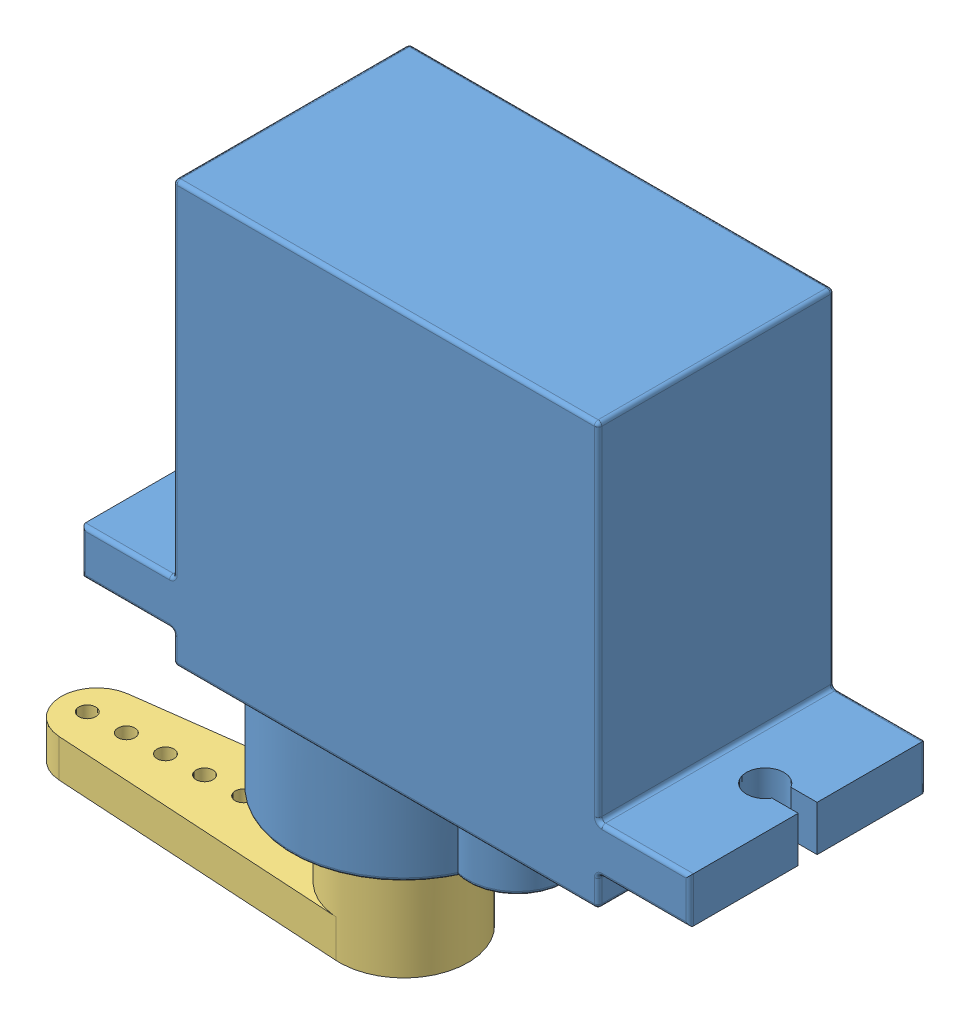
SolidWorks assembly MG90S 金属舵机装配体 2018, configuration 默认. Lengths in mm.
Overall size (39.1 34.99 12.5).
3 component instances, 3 part files, 7 mates.
Components (placement in the parent):
- MG90S 金属舵机渲染2018-1: MG90S 金属舵机渲染2018 [默认] x (-1 0 0) z (0 0 -1) size (32.2 32.2 12.5)
- cross recessed pan head screws gb(GB_CROSS_SCREWS_TYPE1 M2X4-4  H type-N)2018-1: cross recessed pan head screws gb(GB_CROSS_SCREWS_TYPE1 M2X4-4  H type-N)2018 [默认] at (-5.29 -23.85 0) x (0 1 0) z (-0.996226 0 -0.086793) size (5.59 4 4)
- MG90S 金属舵机单舵臂渲染2018-1: MG90S 金属舵机单舵臂渲染2018 [默认] at (-5.29 -23.25 0) x (0.999366 0 -0.035616) z (0 -1 0) size (21 6.8 4.7)
Mates (geometry in assembly coordinates):
- 重合1: coincident anti-aligned: plane of MG90S 金属舵机渲染2018-1 through (0 0 0) normal (0 0 -1)
- 重合2: coincident aligned: plane of MG90S 金属舵机渲染2018-1 through (0 0 0) normal (0 1 0)
- 重合3: coincident anti-aligned: plane of MG90S 金属舵机渲染2018-1 through (0 0 0) normal (-1 0 0)
- 同心1: concentric anti-aligned: cylinder of MG90S 金属舵机渲染2018-1 through (-5.29 -21.05 0) axis (0 1 0) radius 1.3; cylinder of MG90S 金属舵机单舵臂渲染2018-1 through (-5.29 -21.25 0) axis (0 -1 0) radius 3.4
- 同心2: concentric anti-aligned: cylinder of cross recessed pan head screws gb(GB_CROSS_SCREWS_TYPE1 M2X4-4  H type-N)2018-1 through (-5.29 -19.3342 0) axis (0 1 0) radius 1; cylinder of MG90S 金属舵机单舵臂渲染2018-1 through (-5.29 -18.55 0) axis (0 -1 0) radius 1.15
- 重合4: coincident anti-aligned: plane of cross recessed pan head screws gb(GB_CROSS_SCREWS_TYPE1 M2X4-4  H type-N)2018-1 through (-5.1772 -22.25 -1.2951) normal (0 1 0); plane of MG90S 金属舵机单舵臂渲染2018-1 through (-5.29 -22.25 0) normal (0 -1 0)
- 重合5: coincident anti-aligned: plane of MG90S 金属舵机渲染2018-1 through (-5.29 -21.05 0) normal (0 -1 0); plane of MG90S 金属舵机单舵臂渲染2018-1 through (-5.29 -21.05 0) normal (0 1 0)
